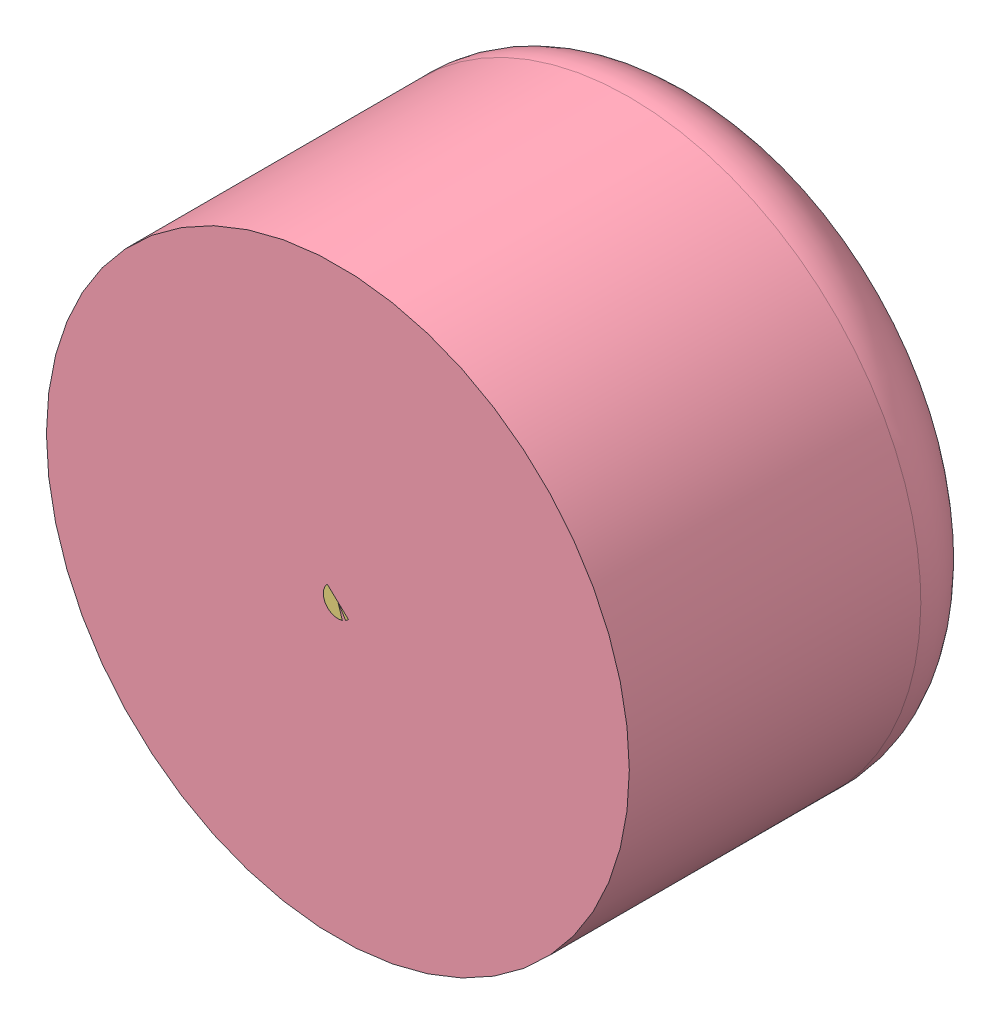
SolidWorks assembly Assem1, configuration Default. Lengths in mm.
Overall size (507.42 507.42 350).
4 component instances, 4 part files, 5 mates.
Components (placement in the parent):
- fan_impeller-1: fan_impeller [Default] at (60.0191 -390.6457 144.4937) size (461 452.59 50)
- rotar_region-2: rotar_region [Default] at (60.0191 -390.6457 144.4937) size (480 480 50)
- shaft-1: shaft [Default] at (60.0191 -390.6457 194.4937) size (25 25 200)
- tank-1: tank [Default] at (60.0191 -390.6457 144.4937) size (507.42 507.42 350)
Mates (geometry in assembly coordinates):
- Concentric2: concentric aligned: circle of fan_impeller-1; circle of rotar_region-2
- Coincident6: coincident aligned: plane of fan_impeller-1 through (60.0191 -390.6457 194.4937) normal (0 0 1); plane of rotar_region-2 through (60.0191 -390.6457 194.4937) normal (0 0 1)
- Coincident8: coincident aligned: circle of fan_impeller-1; circle of shaft-1
- Concentric4: concentric aligned: circle of rotar_region-2; circle of tank-1
- Coincident9: coincident anti-aligned: plane of rotar_region-2 through (60.0191 -390.6457 144.4937) normal (0 0 -1); circle of tank-1
